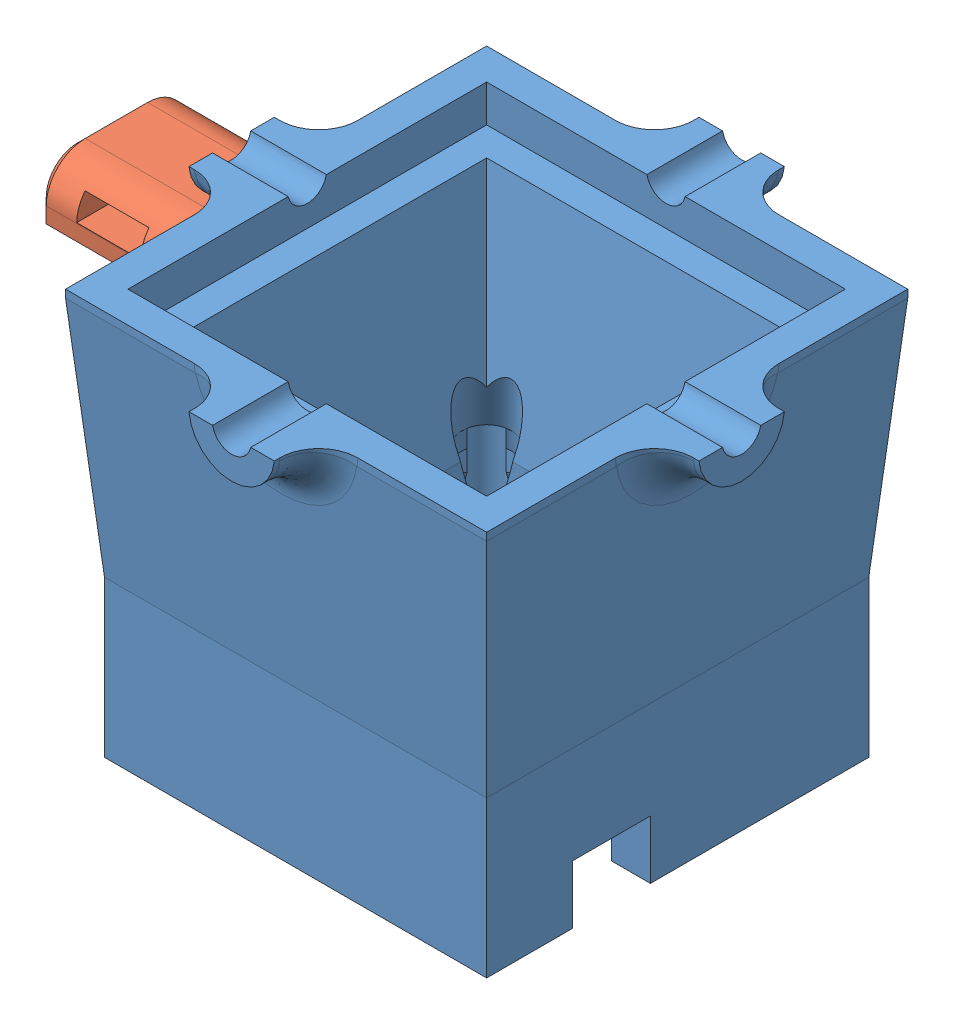
SolidWorks assembly Finger Attachement1, configuration Default. Lengths in mm.
Overall size (81.17 52 65.4).
2 component instances, 2 part files, 3 mates.
Components (placement in the parent):
- Sensor Frame Fisheye Acrilic-1: Sensor Frame Fisheye Acrilic [Default] at (-33.2138 1.5869 12.3721) size (65.4 52 65.4)
- franka_attachement-1: franka_attachement [Default] at (-127.6865 -47.4708 12.3721) x (0 1 0) z (1 0 0) size (7 18 25.47)
Mates (geometry in assembly coordinates):
- Coincident3: coincident aligned: plane of Sensor Frame Fisheye Acrilic-1 through (-56.2138 28.8244 -10.6279) normal (1 0 0); plane of franka_attachement-1 through (-56.2138 23.5869 16.3721) normal (1 0 0)
- Coincident5: coincident aligned: plane of Sensor Frame Fisheye Acrilic-1 through (-33.2138 1.5869 12.3721) normal (0 0 1); plane of franka_attachement-1 through (-127.6865 -47.4708 12.3721) normal (0 0 1)
- Coincident7: coincident: point of Sensor Frame Fisheye Acrilic-1; plane of franka_attachement-1 through (-81.6865 28.5869 21.3721) normal (0 1 0)
